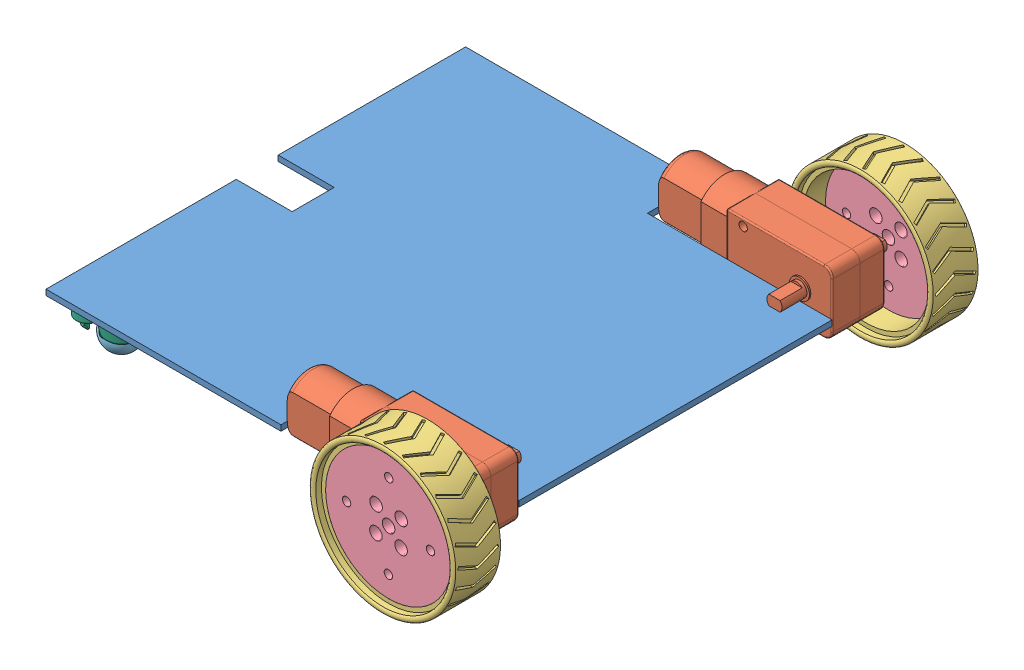
SolidWorks assembly Robot, configuration Default. Lengths in mm.
Overall size (185.14 107.26 198.63).
16 component instances, 7 part files, 16 mates.
Components (placement in the parent):
- Chassie-1: Chassie [Default] at (56.3992 70.6772 119.4071) size (150 2 150)
- wheel-1: wheel [Default] at (172.7232 85.6472 35.5851) x (0 0 -1) z (-0.96637 -0.257157 0) size (52.72 74.46 91.45)
  - dc_motor_with_wheel-1: dc_motor_with_wheel [Défaut] at origin size (37.6 36.38 67.23)
  - tyre-1: tyre [Default] at (1.5267 -5.0802 53) x (1 0 0) z (0 0.34528 0.9385) size (16.83 52 52)
  - wheel_3wholes_outerlayer-1: wheel_3wholes_outerlayer [Default] at (7.5267 -5.0802 53) x (0 -0.603955 0.797018) z (0 -0.797018 -0.603955) size (45 4 45)
- wheel-2: wheel [Default] at (172.7232 68.2072 203.229) x (0 0 1) z (-0.96637 0.257157 0) size (52.72 74.46 91.45)
  - dc_motor_with_wheel-1: dc_motor_with_wheel [Défaut] at origin size (37.6 36.38 67.23)
  - tyre-1: tyre [Default] at (1.5267 -5.0802 53) x (1 0 0) z (0 0.34528 0.9385) size (16.83 52 52)
  - wheel_3wholes_outerlayer-1: wheel_3wholes_outerlayer [Default] at (7.5267 -5.0802 53) x (0 -0.603955 0.797018) z (0 -0.797018 -0.603955) size (45 4 45)
- ball_v2-1: ball_v2 [Default] at (-5.4439 64.9929 174.8852) x (-0.994727 0.101202 0.016649) z (0.102116 0.992387 0.068845) size (19.98 31.23 22.65)
  - ball-1: ball [Predeterminado] at (1.5642 3.9174 -7.4116) x (0.97009 -0.147809 -0.192554) z (0.182549 -0.078633 0.980047) size (12.6 12.6 12.6)
  - bas-1: bas [Predeterminado] at (3.6231 4.1003 3.995) x (-0.016649 -0.997488 -0.068845) z (0.994727 -0.009555 -0.102116) size (28.57 12.2 18.37)
- ball_v2-2: ball_v2 [Default] at (-5.4439 64.9929 55.0782) x (-0.994727 0.101202 0.016649) z (0.102116 0.992387 0.068845) size (19.98 31.23 22.65)
  - ball-1: ball [Predeterminado] at (1.5642 3.9174 -7.4116) x (0.97009 -0.147809 -0.192554) z (0.182549 -0.078633 0.980047) size (12.6 12.6 12.6)
  - bas-1: bas [Predeterminado] at (3.6231 4.1003 3.995) x (-0.016649 -0.997488 -0.068845) z (0.994727 -0.009555 -0.102116) size (28.57 12.2 18.37)
- IR Sensor-1: IR Sensor [Default] at (11.3992 70.6772 121.5961) x (0 0 1) z (1 0 0) size (110 9 22)
Mates (geometry in assembly coordinates):
- Coincident70: coincident anti-aligned: plane of Chassie-1 through (56.3992 70.6772 119.4071) normal (0 -1 0); plane of IR Sensor-1 through (11.3992 70.6772 121.5961) normal (0 1 0)
- Coincident71: coincident aligned: plane of Chassie-1 through (1.3992 70.6762 111.4071) normal (-1 0 0); plane of IR Sensor-1 through (1.3992 68.6772 176.5961) normal (-1 0 0)
- Coincident72: coincident aligned: plane of Chassie-1 through (131.3992 72.6772 44.4071) normal (1 0 0); plane of wheel-2/dc_motor_with_wheel-1 through (131.3992 65.6772 194.2071) normal (1 0 0)
- Coincident73: coincident anti-aligned: plane of Chassie-1 through (131.3992 72.6782 175.4071) normal (0 0 1); plane of wheel-2/dc_motor_with_wheel-1 through (120.1992 76.9272 175.4071) normal (0 0 -1)
- Distance4: distance = 5 mm aligned: plane of Chassie-1 through (56.3992 70.6772 119.4071) normal (0 -1 0); plane of wheel-2/dc_motor_with_wheel-1 through (93.5992 65.6772 194.2071) normal (0 -1 0)
- Coincident75: coincident aligned: plane of Chassie-1 through (131.3992 72.6772 44.4071) normal (1 0 0); plane of wheel-1/dc_motor_with_wheel-1 through (131.3992 88.1772 44.6071) normal (1 0 0)
- Distance3: distance = 5 mm aligned: plane of Chassie-1 through (56.3992 70.6772 119.4071) normal (0 -1 0); plane of wheel-1/dc_motor_with_wheel-1 through (131.3992 65.6772 44.6071) normal (0 -1 0)
- Coincident77: coincident anti-aligned: plane of Chassie-1 through (131.3992 72.6782 63.4071) normal (0 0 -1); plane of wheel-1/dc_motor_with_wheel-1 through (120.1992 76.9272 63.4071) normal (0 0 1)
- Coincident78: coincident anti-aligned: plane of Chassie-1 through (56.3992 70.6772 119.4071) normal (0 -1 0); plane of ball_v2-1/bas-1 through (-2.8642 70.6772 190.2585) normal (0 1 0)
- Coincident79: coincident: line of Chassie-1 through (-8.6008 70.6772 194.4071) axis (0 0 -1)
- Coincident80: coincident: line of Chassie-1 through (-8.6008 70.6772 194.4071) axis (0 0 -1)
- Distance1: distance = 5 mm: line of assembly; point of ball_v2-1/bas-1; line of Chassie-1 through (-18.6008 70.6772 194.4071) axis (1 0 0)
- Coincident82: coincident anti-aligned: plane of Chassie-1 through (56.3992 70.6772 119.4071) normal (0 -1 0); plane of ball_v2-2/bas-1 through (-2.8642 70.6772 70.4515) normal (0 1 0)
- Coincident83: coincident: line of Chassie-1 through (-8.6008 70.6772 194.4071) axis (0 0 -1)
- Coincident84: coincident: line of Chassie-1 through (-8.6008 70.6772 194.4071) axis (0 0 -1)
- Distance2: distance = 5 mm: line of assembly; point of ball_v2-2/bas-1; line of Chassie-1 through (65.3992 70.6772 44.4071) axis (-1 0 0)
